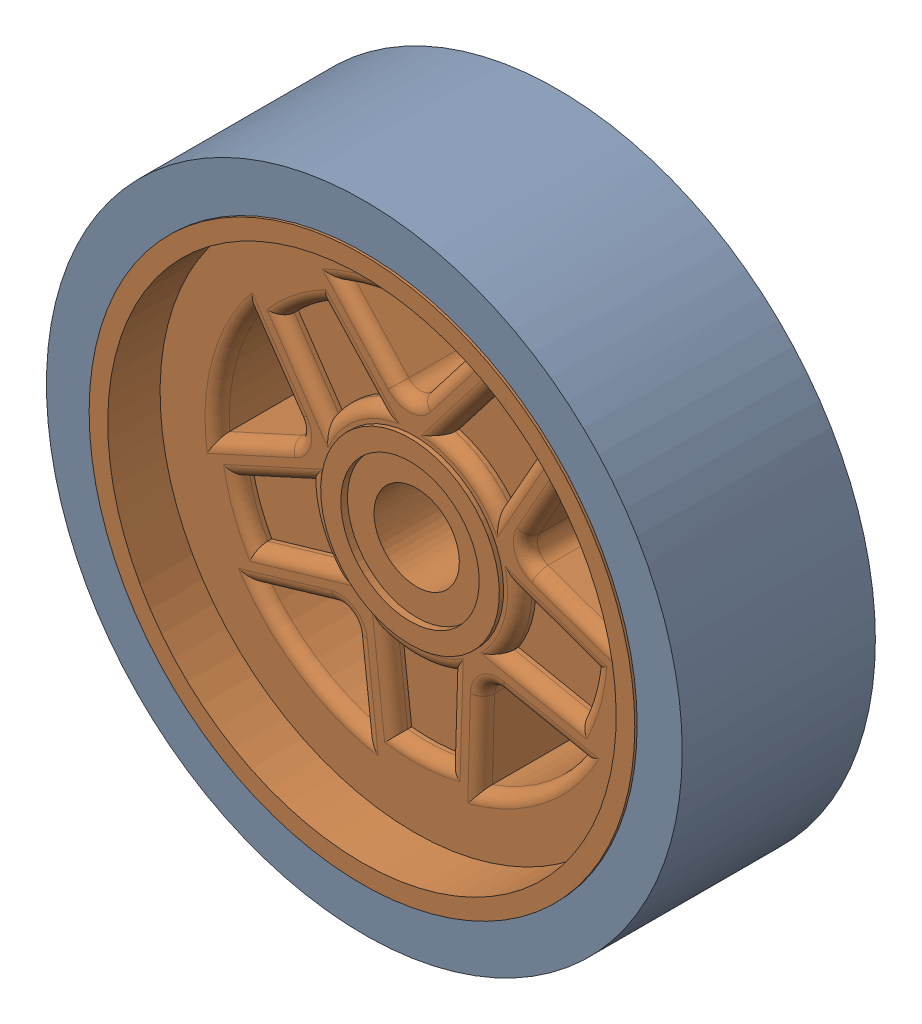
SolidWorks assembly Assem1, configuration Default. Lengths in mm.
Overall size (12.81 12.81 3.09).
2 component instances, 2 part files, 1 mates.
Components (placement in the parent):
- tire-1: tire [Default] at (-2.3934 0.0025 1.2612) size (10.03 10.03 3.05)
- star wheel-1: star wheel [Default] at (-2.3934 0.0025 1.9518) x (0.833415 -0.552648 0) z (0 0 1) size (9.25 9.25 2.72)
Mates (geometry in assembly coordinates):
- Concentric1: concentric aligned: cylinder of tire-1 through (-2.3934 0.0025 -2.5488) axis (0 0 1) radius 4.826; cylinder of star wheel-1 through (-2.3934 0.0025 -2.4351) axis (0 0 1) radius 4.6228
